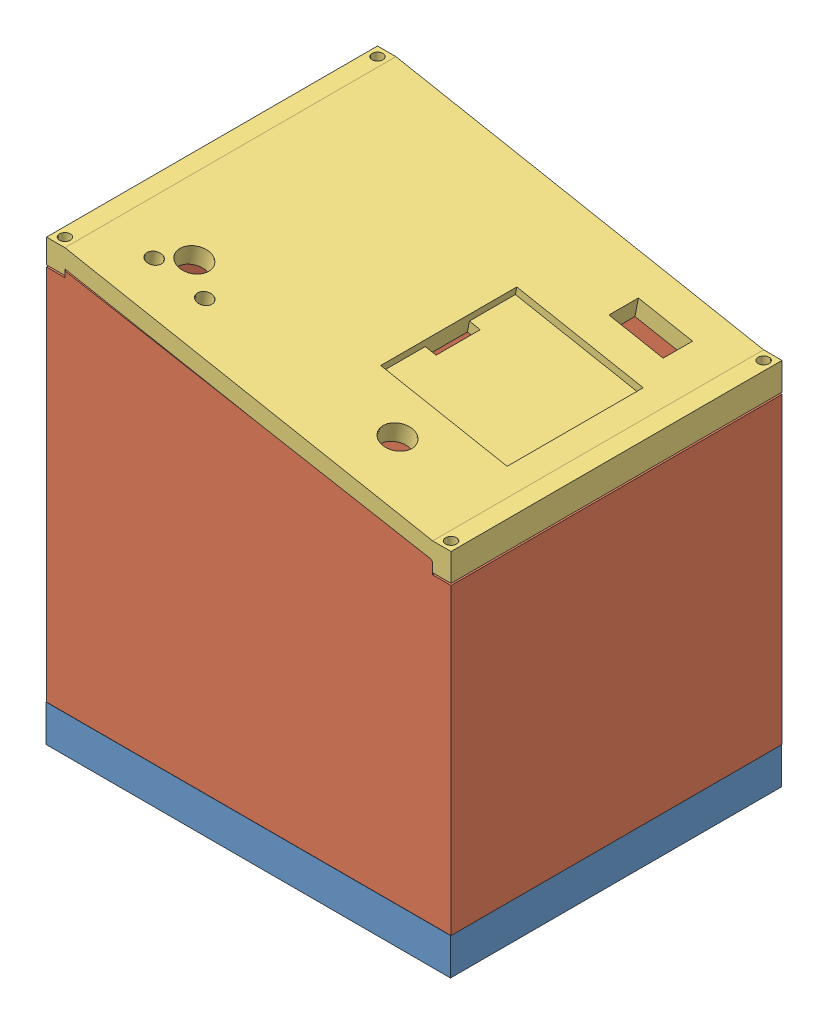
SolidWorks assembly Assem2, configuration Default. Lengths in mm.
Overall size (110.14 119.56 90.01).
3 component instances, 3 part files, 0 mates.
Components (placement in the parent):
- Part1-1: Part1 [Default] at (27.8613 50.9882 95.758) size (110 23 90)
- Part2-1: Part2 [Default] at (28 86 95.75) size (110 104.05 90)
- Part3-1: Part3 [Default] at (28 144 95.75) size (110 26.55 90)
